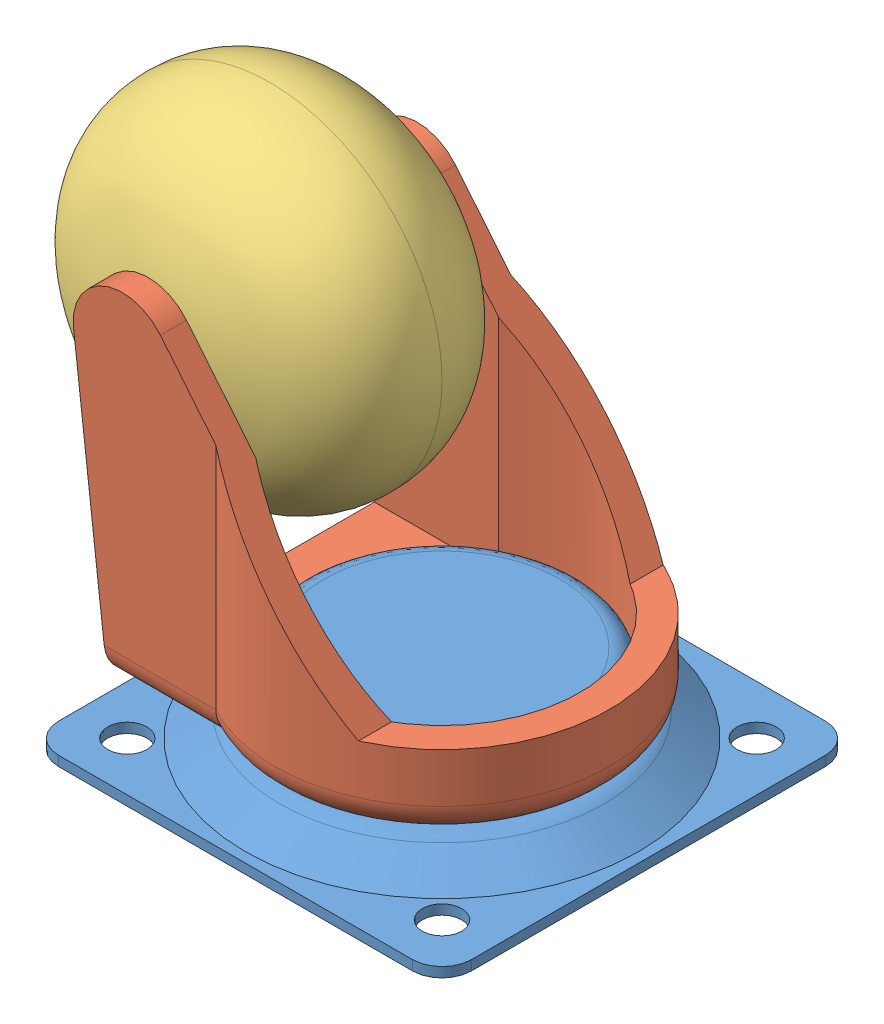
SolidWorks assembly Pivoting_roller, configuration Défaut. Lengths in mm.
Overall size (56 50 42).
3 component instances, 3 part files, 4 mates.
Components (placement in the parent):
- roller_base-1: roller_base [Défaut] at (6.3806 -3.4366 42) size (42 9 42)
- Pivot-1: Pivot [Défaut] at (6.3806 0.5634 42) size (39.5 35 34)
- Roller-1: Roller [Défaut] at (-11.1194 29.0634 42) x (0 0 1) z (-1 0 0) size (23.75 35 35)
Mates (geometry in assembly coordinates):
- Coaxiale1: concentric anti-aligned: cylinder of roller_base-1 through (6.3806 0.5634 42) axis (0 1 0) radius 14; cylinder of Pivot-1 through (6.3806 35.5634 42) axis (0 -1 0) radius 14
- Coïncidente1: coincident anti-aligned: plane of roller_base-1 through (6.3806 0.5634 56.7697) normal (0 1 0); circle of Pivot-1
- Coaxiale2: concentric anti-aligned: cylinder of Pivot-1 through (-11.1194 29.0634 57) axis (0 0 -1) radius 3; cylinder of Roller-1 through (-11.1194 29.0634 30) axis (0 0 1) radius 3
- Coïncidente2: coincident aligned: plane of Pivot-1 through (6.3806 0.5634 42) normal (0 0 1); plane of Roller-1 through (-11.1194 29.0634 42) normal (0 0 1)
